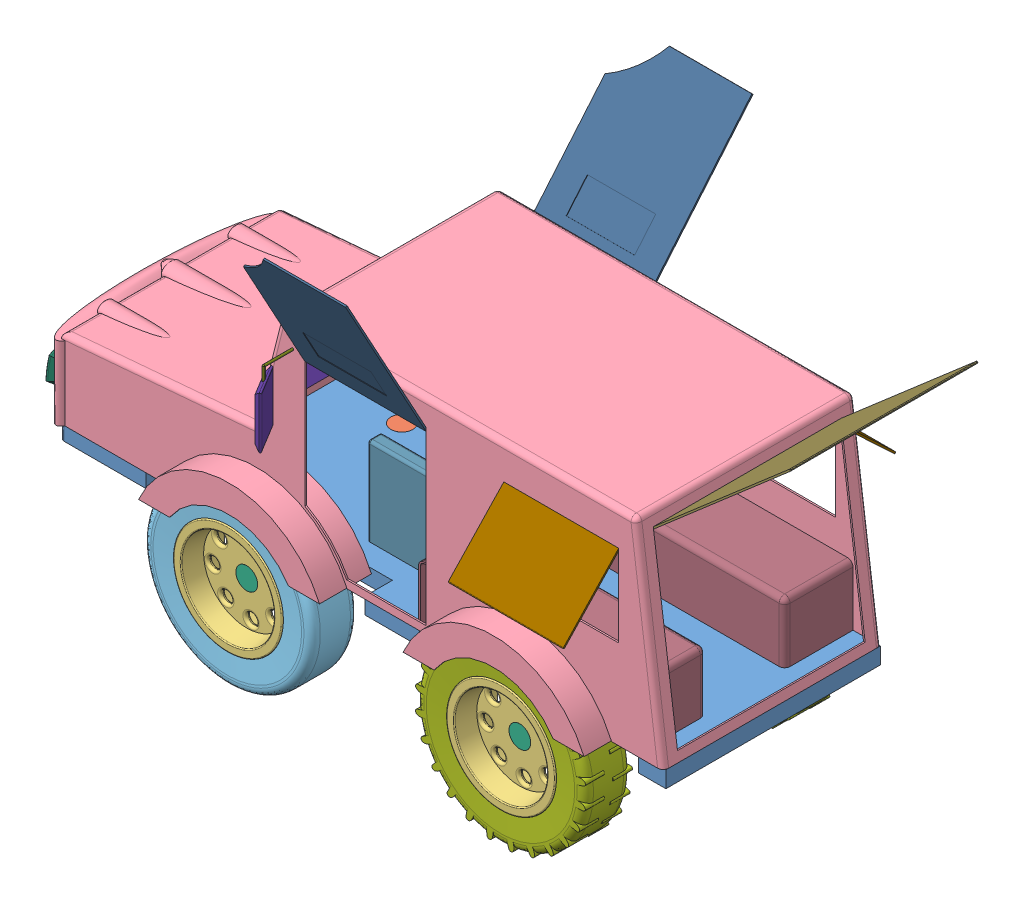
SolidWorks assembly 装配体3, configuration 默认. Lengths in mm.
Overall size (1367.41 875.21 744.93).
34 component instances, 17 part files, 80 mates.
Components (placement in the parent):
- 底盘-1: 底盘 [默认] at (-145.7905 -0.8691 0) size (1135 30 392.05)
- 钉-1: 钉 [默认] at (-345.7688 -34.4785 81.4627) size (120 88.31 60)
- 钉-2: 钉 [默认] at (-345.7688 -34.4785 -141.4627) size (120 88.31 60)
- 轮-1: 轮 [默认] at (-302.0207 -124.4013 -242.7801) x (-0.437481 0.899228 0) z (0.899228 0.437481 0) size (200 80 200)
- 轮-2: 轮 [默认] at (-444.9603 -47.1689 247.2199) x (0.991915 0.126904 0) z (-0.126904 0.991915 0) size (200 80 200)
- 盖-1: 盖 [Default] at (-145.7905 29.1309 0.9762) x (-1 0 0) z (0 0 -1) size (1156.36 375 500)
- 前胎-2: 前胎 [默认] at (-345.7688 -34.4785 162.7199) x (0.991915 0.126904 0) z (0 0 1) size (310 310 85)
- 前胎-3: 前胎 [默认] at (-345.7688 -34.4785 -246.2874) x (-0.899228 -0.437481 0) z (0 0 1) size (310 310 85)
- 好轴-2: 好轴 [默认] at (-345.7688 -34.4785 -207.7801) x (0.997458 0.071258 0) z (0 0 1) size (40 40 420)
- 钉-3: 钉 [默认] at (154.2312 -34.4785 -141.4627) size (120 88.31 60)
- 钉-4: 钉 [默认] at (154.2312 -34.4785 81.4627) size (120 88.31 60)
- 好轴-3: 好轴 [默认] at (154.2312 -34.4785 -207.0038) x (0.402868 -0.915258 0) z (0 0 1) size (40 40 420)
- 胎-1: 胎 [默认] at (185.1325 -18.142 -242.5038) x (-0.985844 0.167666 0) z (0 0 1) size (312.99 312.99 86.91)
- 轮-3: 轮 [默认] at (93.0112 44.5918 -162.0038) x (0.6122 -0.790703 0) z (0.790703 0.6122 0) size (200 80 200)
- 轮-4: 轮 [默认] at (141.5793 64.7179 247.9962) x (0.126519 -0.991964 0) z (0.991964 0.126519 0) size (200 80 200)
- 胎-2: 胎 [默认] at (144.5609 -68.0681 163.4962) x (0.804654 0.593743 0) z (0 0 1) size (312.99 312.99 86.91)
- 前窗-1: 前窗 [默认] at (-310.964 331.673 -57.3297) x (0 0 1) z (0.983818 -0.17917 0) size (147.3 156.9 3)
- haochuang-1: haochuang [默认] at (309.0495 239.4568 292.8434) x (1 0 0) z (0 0.687389 0.726289) size (210 150 3)
- haochuang-2: haochuang [默认] at (309.0495 247.365 -298.7648) x (1 0 0) z (0 -0.729292 0.684203) size (210 150 3)
- ahomen-1: ahomen [默认] at (402.1523 636.9331 -436.5862) x (1 0 0) z (0 -0.644767 -0.764379) size (221.6 309 3)
- 前窗-2: 前窗 [默认] at (-312.6534 332.0756 132.6703) x (0 0 1) z (0.975984 -0.217842 0) size (147.3 156.9 3)
- 雨刷-1: 雨刷 [默认] at (-317.7102 304.0831 22.2799) x (0 0 1) z (-0.970143 0.242536 0) size (149 15 6)
- 雨刷-2: 雨刷 [默认] at (-318.3054 301.7022 -167.7201) x (0 0 1) z (-0.970143 0.242536 0) size (149 15 6)
- 正确后门-1: 正确后门 [默认] at (480.8497 485.5924 0.9762) x (0.654561 -0.756009 0) z (0 0 1) size (3 334 343)
- 椅-1: 椅 [默认] at (154.2095 84.1309 -196.0238) size (400 110 125)
- 椅-2: 椅 [默认] at (154.2095 84.1309 197.9762) x (-1 0 0) z (0 0 -1) size (400 110 125)
- 前椅-5: 前椅 [默认] at (-110.7905 109.1309 -6.9762) x (0 0 1) z (0 -1 0) size (306 192.93 337.82)
- dneg-1: dneg [默认] at (-740.4522 94.8241 -146.3129) x (-0.108423 0.150334 -0.982672) z (0.992444 -0.040742 -0.115734) size (71.49 75.56 46.93)
- dneg-2: dneg [默认] at (-731.3988 91.0427 159.4035) x (0.000498 0.008561 -0.999963) z (0.999963 -0.008565 0.000425) size (71.49 75.56 46.93)
- lianjiet-1: lianjiet [默认] at (-273.7055 313.636 -251.8026) x (0 0 -1) z (-0.999126 0.041792 0) size (56.78 49 8)
- jing-1: jing [默认] at (-270.9014 280.0767 -249.1679) x (0.041792 0.999126 0) z (-0.530569 0.022193 0.847351) size (94.34 10 64.34)
- lianjiet-2: lianjiet [默认] at (-273.1711 315.881 253.755) x (0 0 1) z (1 0 0) size (56.78 49 8)
- jing-2: jing [默认] at (-269.054 290.4668 251.2584) x (0 1 0) z (0.518516 0 0.855068) size (94.34 10 64.34)
- ahomen-3: ahomen [默认] at (402.1769 677.5718 379.1295) x (1 0 0) z (0 0.478689 -0.877985) size (221.6 309 3)
Mates (geometry in assembly coordinates):
- 同心1: concentric aligned: cylinder of 底盘-1 through (-385.7905 29.1309 111.4627) axis (0 -1 0) radius 20; cylinder of 钉-1 through (-385.7905 29.1309 111.4627) axis (0 -1 0) radius 20
- 重合1: coincident anti-aligned: circle of 底盘-1; cylinder of 钉-1 through (-305.7905 29.1309 111.4627) axis (0 -1 0) radius 20
- 重合2: coincident anti-aligned: plane of 底盘-1 through (-1098.4513 -0.8691 -1.9881) normal (0 -1 0); plane of 钉-1 through (-345.7905 -0.8691 141.4627) normal (0 1 0)
- 重合3: coincident anti-aligned: circle of 底盘-1; cylinder of 钉-2 through (-385.7905 29.1309 -111.4627) axis (0 -1 0) radius 20
- 重合4: coincident aligned: circle of 底盘-1; cylinder of 钉-2 through (-305.7905 29.1309 -111.4627) axis (0 -1 0) radius 20
- 重合5: coincident anti-aligned: plane of 底盘-1 through (-1098.4513 -0.8691 -1.9881) normal (0 -1 0); plane of 钉-2 through (-345.7905 -0.8691 -81.4627) normal (0 1 0)
- 重合11: coincident anti-aligned: plane of 底盘-1 through (-1098.4513 29.1309 -1.9881) normal (0 1 0); plane of 盖-1 through (-695.7905 29.1309 -199.0238) normal (0 -1 0)
- 重合12: coincident anti-aligned: line of 底盘-1 through (404.2095 29.1309 -196.0238) axis (0 0 1); line of 盖-1 through (404.2095 29.1309 190.9762) axis (0 0 -1)
- 重合13: coincident anti-aligned: line of 底盘-1 through (354.2095 29.1309 -196.0238) axis (1 0 0); line of 盖-1 through (394.121 29.1309 -196.0238) axis (-1 0 0)
- 同心2: concentric aligned: circle of 轮-2; circle of 前胎-2
- 重合15: coincident anti-aligned: circle of 轮-2; circle of 前胎-2
- 同心3: concentric aligned: circle of 轮-1; circle of 前胎-3
- 重合16: coincident anti-aligned: circle of 轮-1; circle of 前胎-3
- 同心8: concentric anti-aligned: cylinder of 轮-2 through (-345.7688 -34.4785 167.2199) axis (0 0 1) radius 20; cylinder of 好轴-2 through (-345.7688 -34.4785 212.2199) axis (0 0 -1) radius 20
- 重合32: coincident aligned: plane of 轮-2 through (-345.7688 -34.4785 212.2199) normal (0 0 1); plane of 好轴-2 through (-345.7688 -34.4785 212.2199) normal (0 0 1)
- 同心9: concentric anti-aligned: circle of 前胎-3; cylinder of 好轴-2 through (-345.7688 -34.4785 212.2199) axis (0 0 -1) radius 20
- 重合33: coincident aligned: plane of 轮-1 through (-345.7688 -34.4785 -207.7801) normal (0 0 -1); plane of 好轴-2 through (-345.7688 -34.4785 -207.7801) normal (0 0 -1)
- 同心10: concentric aligned: cylinder of 钉-2 through (-345.7688 -34.4785 -81.4627) axis (0 0 -1) radius 20; cylinder of 好轴-2 through (-345.7688 -34.4785 212.2199) axis (0 0 -1) radius 20
- 锁定2: lock: unknown of 钉-2; unknown of 好轴-2
- 重合34: coincident aligned: plane of 轮-2 through (-444.9603 -47.1689 247.2199) normal (-0.126904 0.991915 0); plane of 前胎-2
- 重合35: coincident anti-aligned: plane of 轮-1 through (-302.0207 -124.4013 -242.7801) normal (0.899228 0.437481 0); plane of 前胎-3
- 重合36: coincident anti-aligned: circle of 底盘-1; cylinder of 钉-3 through (114.2095 29.1309 -111.4627) axis (0 -1 0) radius 20
- 重合37: coincident aligned: circle of 底盘-1; cylinder of 钉-3 through (194.2095 29.1309 -111.4627) axis (0 -1 0) radius 20
- 重合38: coincident anti-aligned: plane of 底盘-1 through (-1098.4513 -0.8691 -1.9881) normal (0 -1 0); plane of 钉-3 through (154.2095 -0.8691 -81.4627) normal (0 1 0)
- 同心11: concentric aligned: cylinder of 底盘-1 through (114.2095 29.1309 111.4627) axis (0 -1 0) radius 20; cylinder of 钉-4 through (114.2095 29.1309 111.4627) axis (0 -1 0) radius 20
- 重合40: coincident anti-aligned: circle of 底盘-1; cylinder of 钉-4 through (194.2095 29.1309 111.4627) axis (0 -1 0) radius 20
- 重合41: coincident anti-aligned: plane of 底盘-1 through (-1098.4513 -0.8691 -1.9881) normal (0 -1 0); plane of 钉-4 through (154.2095 -0.8691 141.4627) normal (0 1 0)
- 同心12: concentric aligned: cylinder of 钉-3 through (154.2312 -34.4785 -81.4627) axis (0 0 -1) radius 20; cylinder of 好轴-3 through (154.2312 -34.4785 212.9962) axis (0 0 -1) radius 20
- 重合42: coincident anti-aligned: cylinder of 好轴-3 through (154.2312 -34.4785 212.9962) axis (0 0 -1) radius 20; circle of 轮-3
- 重合43: coincident aligned: plane of 好轴-3 through (154.2312 -34.4785 -207.0038) normal (0 0 -1); plane of 轮-3 through (154.2312 -34.4785 -207.0038) normal (0 0 -1)
- 同心13: concentric aligned: circle of 胎-1; circle of 轮-3
- 重合44: coincident aligned: circle of 胎-1; circle of 轮-3
- 重合46: coincident anti-aligned: cylinder of 好轴-3 through (154.2312 -34.4785 212.9962) axis (0 0 -1) radius 20; circle of 轮-4
- 重合47: coincident aligned: plane of 好轴-3 through (154.2312 -34.4785 212.9962) normal (0 0 1); plane of 轮-4 through (154.2312 -34.4785 212.9962) normal (0 0 1)
- 锁定3: lock: unknown of 钉-3; unknown of 好轴-3
- 重合49: coincident anti-aligned: circle of 轮-4; circle of 胎-2
- 同心14: concentric anti-aligned: cylinder of 盖-1 through (-301.6069 374.6808 174.8652) axis (0 0 -1) radius 1; cylinder of 前窗-1 through (-301.6069 374.6808 -166.1275) axis (0 0 1) radius 1
- 重合50: coincident anti-aligned: plane of 盖-1 through (-261.8443 280.1603 -18.8275) normal (0 0 -1); plane of 前窗-1 through (-327.9742 221.5267 -18.8275) normal (0 0 1)
- 同心15: concentric anti-aligned: cylinder of 盖-1 through (325.2846 340.2899 199.4762) axis (-1 0 0) radius 1; cylinder of haochuang-1 through (112.4562 340.2899 199.4762) axis (1 0 0) radius 1
- 重合51: coincident anti-aligned: plane of 盖-1 through (112.4562 341.7899 -315.0238) normal (1 0 0); plane of haochuang-1 through (112.4562 342.4104 199.5345) normal (-1 0 0)
- 同心16: concentric aligned: cylinder of 盖-1 through (89.4263 340.2899 -197.5238) axis (1 0 0) radius 1; cylinder of haochuang-2 through (112.4562 340.2899 -197.5238) axis (1 0 0) radius 1
- 重合53: coincident anti-aligned: plane of 盖-1 through (322.4562 341.7899 -315.0238) normal (-1 0 0); plane of haochuang-2 through (322.4562 340.2223 -195.4036) normal (1 0 0)
- 同心18: concentric aligned: cylinder of 盖-1 through (-262.3449 351.1953 -197.5238) axis (1 0 0) radius 1; cylinder of ahomen-1 through (-250.9396 351.1953 -197.5238) axis (1 0 0) radius 1
- 重合54: coincident anti-aligned: plane of 盖-1 through (-250.9396 210.6822 -315.0238) normal (1 0 0); plane of ahomen-1 through (-250.9396 1210.89 -924.6536) normal (-1 0 0)
- 同心20: concentric anti-aligned: cylinder of 盖-1 through (-301.6069 374.6808 174.8652) axis (0 0 -1) radius 1; cylinder of 前窗-2 through (-301.6069 374.6808 23.8725) axis (0 0 1) radius 1
- 重合56: coincident anti-aligned: plane of 盖-1 through (-261.8443 280.1603 171.1725) normal (0 0 -1); plane of 前窗-2 through (-333.9955 222.6861 171.1725) normal (0 0 1)
- 同心21: concentric anti-aligned: cylinder of 盖-1 through (-300.5571 378.8799 22.2799) axis (-0.242536 -0.970143 0) radius 1; cylinder of 雨刷-1 through (-352.7566 170.0821 22.2799) axis (0.242536 0.970143 0) radius 1
- 重合57: coincident anti-aligned: plane of 盖-1 through (-277.9027 475.6822 -199.0238) normal (-0.970143 0.242536 0); plane of 雨刷-1 through (-322.4396 297.5346 169.7799) normal (0.970143 -0.242536 0)
- 同心22: concentric anti-aligned: cylinder of 盖-1 through (-300.5571 378.8799 -167.7201) axis (-0.242536 -0.970143 0) radius 1; cylinder of 雨刷-2 through (-353.3518 167.7013 -167.7201) axis (0.242536 0.970143 0) radius 1
- 重合58: coincident anti-aligned: plane of 盖-1 through (-277.9027 475.6822 -199.0238) normal (-0.970143 0.242536 0); plane of 雨刷-2 through (-323.0348 295.1537 -20.2201) normal (0.970143 -0.242536 0)
- 同心23: concentric aligned: cylinder of 盖-1 through (356.7121 376.1285 -178.5537) axis (0 0 1) radius 1; cylinder of 正确后门-1 through (356.7121 376.1285 -170.5238) axis (0 0 1) radius 1
- 重合59: coincident anti-aligned: plane of 盖-1 through (371.8499 -204.8539 -170.5238) normal (0 0 1); plane of 正确后门-1 through (609.0669 592.6361 -170.5238) normal (0 0 -1)
- 锁定4: lock: unknown of 轮-4; unknown of 胎-2
- 锁定5: lock: unknown of 胎-1; unknown of 轮-3
- 重合62: coincident anti-aligned: plane of 盖-1 through (404.2095 204.1309 -196.0238) normal (0 0 1); plane of 椅-1 through (354.2095 29.1309 -196.0238) normal (0 0 -1)
- 重合63: coincident anti-aligned: plane of 底盘-1 through (-1098.4513 29.1309 -1.9881) normal (0 1 0); plane of 椅-1 through (-45.7905 29.1309 -71.0238) normal (0 -1 0)
- 重合65: coincident anti-aligned: plane of 底盘-1 through (-45.7905 29.1309 -1.9881) normal (1 0 0); plane of 椅-1 through (-45.7905 139.1309 -71.0238) normal (-1 0 0)
- 重合66: coincident anti-aligned: plane of 底盘-1 through (-1098.4513 29.1309 -1.9881) normal (0 1 0); plane of 椅-2 through (354.2095 29.1309 72.9762) normal (0 -1 0)
- 重合67: coincident anti-aligned: plane of 盖-1 through (404.2095 204.1309 197.9762) normal (0 0 -1); plane of 椅-2 through (-45.7905 29.1309 197.9762) normal (0 0 1)
- 重合68: coincident anti-aligned: plane of 底盘-1 through (-45.7905 29.1309 -1.9881) normal (1 0 0); plane of 椅-2 through (-45.7905 139.1309 72.9762) normal (-1 0 0)
- 重合80: coincident anti-aligned: plane of 底盘-1 through (-1098.4513 29.1309 -1.9881) normal (0 1 0); plane of 前椅-5 through (-139.2879 29.1309 35.2526) normal (0 -1 0)
- 重合81: coincident anti-aligned: plane of 椅-2 through (-45.7905 139.1309 72.9762) normal (-1 0 0); plane of 前椅-5 through (-45.7905 520.0393 -195.9762) normal (1 0 0)
- 重合82: coincident aligned: plane of 底盘-1 through (-1098.4513 29.1309 146.0238) normal (0 0 1); plane of 前椅-5 through (-250.7905 -10.8691 146.0238) normal (0 0 1)
- 相切1: tangent: face of 盖-1; plane of dneg-1 through (-710.581 72.9309 -184.871) normal (0.992444 -0.040742 -0.115734)
- 相切3: tangent: face of 盖-1; plane of dneg-2 through (-696.6028 65.5204 127.8412) normal (0.999963 -0.008565 0.000425)
- 锁定8: lock: unknown of dneg-1; unknown of dneg-2
- 锁定9: lock: unknown of 盖-1; unknown of dneg-1
- 重合83: coincident anti-aligned: plane of 盖-1 through (404.2095 204.1309 -199.0238) normal (0 0 -1); plane of lianjiet-1 through (-226.2978 354.6906 -199.0238) normal (0 0 1)
- 同心28: concentric anti-aligned: cylinder of lianjiet-1 through (-273.6219 315.6343 -251.8026) axis (-0.041792 -0.999126 0) radius 2; cylinder of jing-1 through (-272.8116 335.0044 -251.8026) axis (0.041792 0.999126 0) radius 2
- 相切5: tangent anti-aligned: sphere of lianjiet-1; sphere of jing-1
- 垂直1: perpendicular: line of 盖-1 through (-250.9396 352.6953 -199.0238) axis (0 -1 0); cylinder of lianjiet-1 through (-271.9084 356.5985 -251.3087) axis (0 0 -1) radius 2
- 垂直2: perpendicular: line of 盖-1 through (-250.9396 352.6953 -199.0238) axis (1 0 0); cylinder of lianjiet-1 through (-271.9084 356.5985 -251.3087) axis (0 0 -1) radius 2
- 锁定10: lock: unknown of 盖-1; unknown of lianjiet-1
- 同心32: concentric: sphere of lianjiet-2; sphere of jing-2
- 平行3: parallel anti-aligned: cylinder of lianjiet-2 through (-273.1711 317.881 253.755) axis (0 -1 0) radius 2; cylinder of jing-2 through (-273.2964 345.2667 253.831) axis (0 1 0) radius 2
- 重合85: coincident anti-aligned: plane of 盖-1 through (404.2095 204.1309 200.9762) normal (0 0 1); plane of lianjiet-2 through (-318.8215 358.881 200.9762) normal (0 0 -1)
- 平行4: parallel aligned: line of 盖-1 through (-250.9396 352.6953 200.9762) axis (0 -1 0); cylinder of lianjiet-2 through (-273.1711 317.881 253.755) axis (0 -1 0) radius 2
- 锁定11: lock: unknown of 盖-1; unknown of lianjiet-2
- 同心39: concentric anti-aligned: cylinder of 盖-1 through (-26.4866 351.1953 199.4762) axis (-1 0 0) radius 1; cylinder of ahomen-3 through (-250.915 351.1953 199.4762) axis (1 0 0) radius 1
- 重合87: coincident anti-aligned: plane of 盖-1 through (-29.315 210.6822 -315.0238) normal (-1 0 0); plane of ahomen-3 through (-29.315 1340.4907 737.1447) normal (1 0 0)
